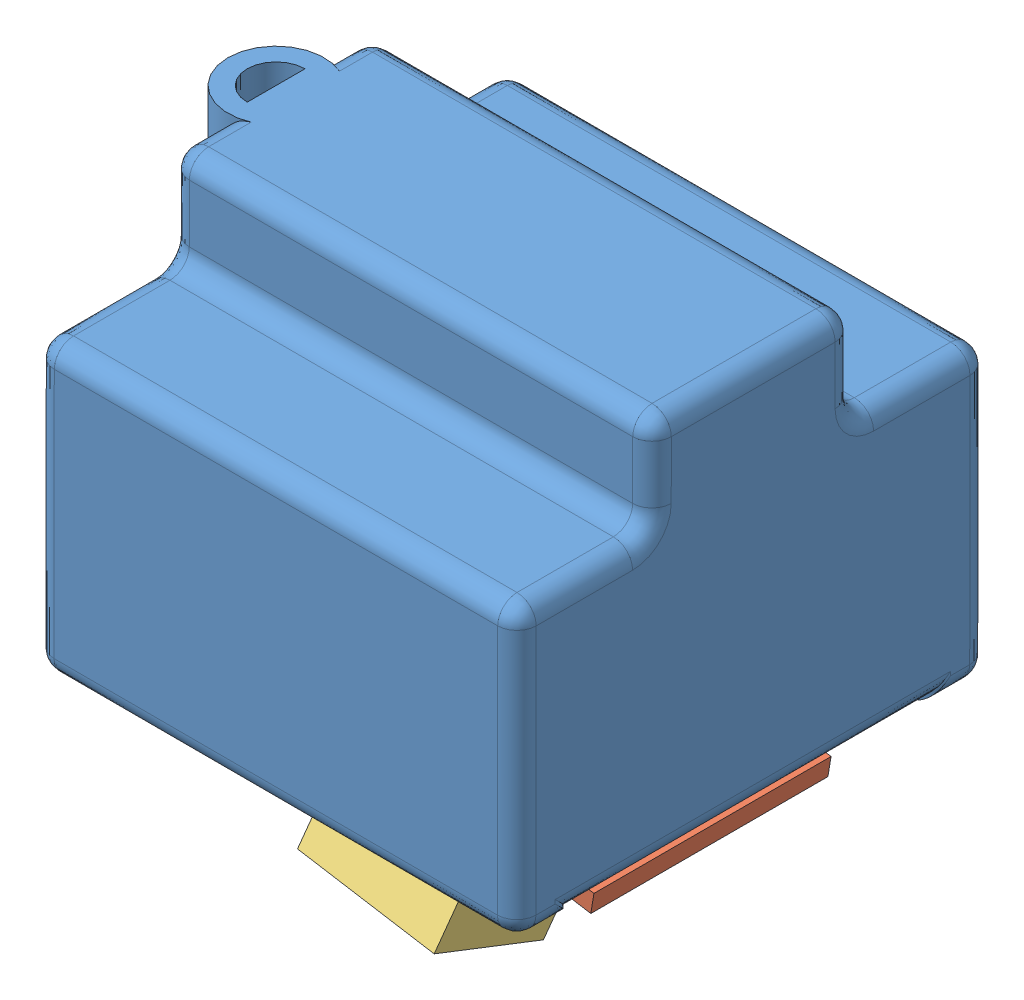
SolidWorks assembly Ankle assembly, configuration Default. Lengths in mm.
Overall size (69.91 80.97 62.23).
6 component instances, 6 part files, 17 mates.
Components (placement in the parent):
- Ty talus-1: Ty talus [Default] at (-11.1955 -30.5954 -4.6279) x (0 0 1) z (-0.999999 0.001115 0) size (62.23 50.8 69.85)
- Ty Part 2-1: Ty Part 2 [Default] at (-40.405 -30.0548 6.0401) x (0 0 1) z (0.986652 -0.162845 0) size (45.97 24.51 48.01)
- Part 3 Talus-1: Part 3 Talus [Default] at (-24.529 -35.2495 26.4871) x (0.065361 0.396009 0.915918) z (-0.986652 0.162845 0) size (27.65 35.05 34.71)
- Part 5 Ty-1: Part 5 Ty [Default] at (-39.1896 -32.8298 -2.3338) x (-0.986652 0.162845 0) z (0 0 -1) size (22.86 14.73 2.03)
- Part 4 Ty-1: Part 4 Ty [Default] at (-57.9186 -28.7089 19.656) x (0 0 -1) z (0.986652 -0.162845 0) size (38.1 5.08 9.4)
- Ankle shell-1: Ankle shell [Default] at (-40.405 -30.0548 47.4421) x (0 0 -1) z (-0.986652 0.162845 0) size (40.89 25.4 50.8)
Mates (geometry in assembly coordinates):
- Concentric1: concentric: cylinder of Ty Part 2-1 through (-55.2286 -30.1826 26.4871) axis (-0.986652 0.162845 0) radius 13.335; cylinder of Part 3 Talus-1 through (-24.529 -35.2495 26.4871) axis (0.986652 -0.162845 0) radius 13.081
- Coincident1: coincident: plane of Ty Part 2-1 through (-24.529 -35.2495 39.8221) normal (-0.986652 0.162845 0); plane of Part 3 Talus-1 through (-24.529 -35.2495 26.4871) normal (0.986652 -0.162845 0)
- Concentric2: concentric: circle of Ty Part 2-1; circle of Ankle shell-1
- Coincident2: coincident: point of Ty Part 2-1; circle of Ankle shell-1
- Concentric3: concentric: circle of Ty talus-1; circle of Ankle shell-1
- Parallel1: parallel: plane of Ty Part 2-1 through (-40.405 -30.0548 6.0401) normal (-0.162845 -0.986652 0); plane of Ankle shell-1 through (-40.405 -30.0548 47.4421) normal (-0.162845 -0.986652 0)
- Coincident3: coincident: plane of Ty talus-1 through (-15.0021 -27.5432 47.4421) normal (0 0 -1); plane of Ankle shell-1 through (-40.405 -30.0548 47.4421) normal (0 0 1)
- Coincident4: coincident: line of Ty Part 2-1 through (-58.0729 -27.1388 47.4421) axis (0.162845 0.986652 0); line of Part 4 Ty-1 through (-57.6593 -24.6327 47.4421) axis (-0.162845 -0.986652 0)
- Parallel2: parallel: plane of Part 4 Ty-1 through (-57.6593 -24.6327 47.4421) normal (0 0 1); plane of Ankle shell-1 through (-40.405 -30.0548 47.4421) normal (0 0 1)
- Coincident5: coincident: plane of Ty Part 2-1 through (-39.9913 -27.5487 6.0401) normal (-0.162845 -0.986652 0); line of Part 4 Ty-1 through (-59.9148 -24.2604 47.4421) axis (0.986652 -0.162845 0)
- Parallel3: parallel: plane of Ty Part 2-1 through (-26.3453 -22.0779 11.1201) normal (0 0 1); plane of Part 5 Ty-1 through (-27.3477 -21.9125 13.4061) normal (0 0 1)
- Concentric4: concentric: circle of Ty Part 2-1; cylinder of Part 5 Ty-1 through (-38.2942 -18.0463 12.3901) axis (-0.162845 -0.986652 0) radius 1.016
- Distance1: distance = 0 mm: plane of Part 5 Ty-1 through (-39.1896 -32.8298 -2.3338) normal (-0.162845 -0.986652 0); plane of Ty Part 2-1 through (-40.8186 -32.5609 6.0401) normal (-0.162845 -0.986652 0)
- LimitAngle1: limit planar angle = 0.710205 rad: plane of Part 4 Ty-1 through (-67.3455 -25.6083 47.4421) normal (0.162845 0.986652 0); plane of Ty talus-1 through (-59.1558 -7.6578 -4.6279) normal (-0.76676 -0.641933 0)
- LimitAngle2: limit planar angle = 0.511525 rad: plane of Ty talus-1 through (-12.9454 -20.095 -4.6279) normal (0.340972 -0.940073 0); plane of Ty Part 2-1 through (-40.405 -30.0548 6.0401) normal (0.162845 0.986652 0)
- LimitAngle3: limit planar angle = 0.023324 rad: plane of Part 3 Talus-1 through (-24.589 -35.6135 39.5925) normal (0.162801 0.986383 0.023322); plane of Ty Part 2-1 through (-40.8186 -32.5609 6.0401) normal (-0.162845 -0.986652 0)
- LimitAngle4: limit planar angle = 2.218545 rad: plane of Ty Part 2-1 through (-40.8186 -32.5609 6.0401) normal (-0.162845 -0.986652 0); plane of Part 3 Talus-1 through (-26.5238 -47.3357 17.202) normal (0.09826 0.595338 -0.797444)
